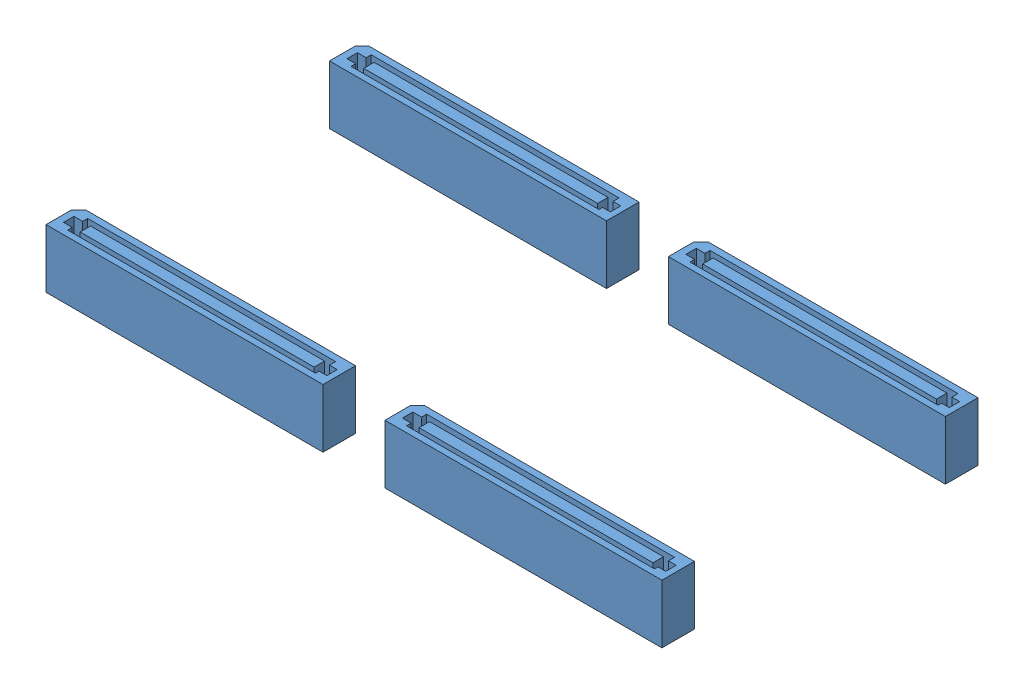
SolidWorks assembly board-interconnects.120-pin.top-SV5, configuration Default. Lengths in mm.
Overall size (94.5 9 48.5).
4 component instances, 1 part files, 0 mates.
Components (placement in the parent):
- board-interconnects.120-pin.top-SV5-1: board-interconnects.120-pin.top-SV5 [Default] at origin size (42.5 9 5)
- board-interconnects.120-pin.top-SV5-2: board-interconnects.120-pin.top-SV5 [Default] at (0 0 -43.5) size (42.5 9 5)
- board-interconnects.120-pin.top-SV5-3: board-interconnects.120-pin.top-SV5 [Default] at (52 0 0) size (42.5 9 5)
- board-interconnects.120-pin.top-SV5-4: board-interconnects.120-pin.top-SV5 [Default] at (52 0 -43.5) size (42.5 9 5)
